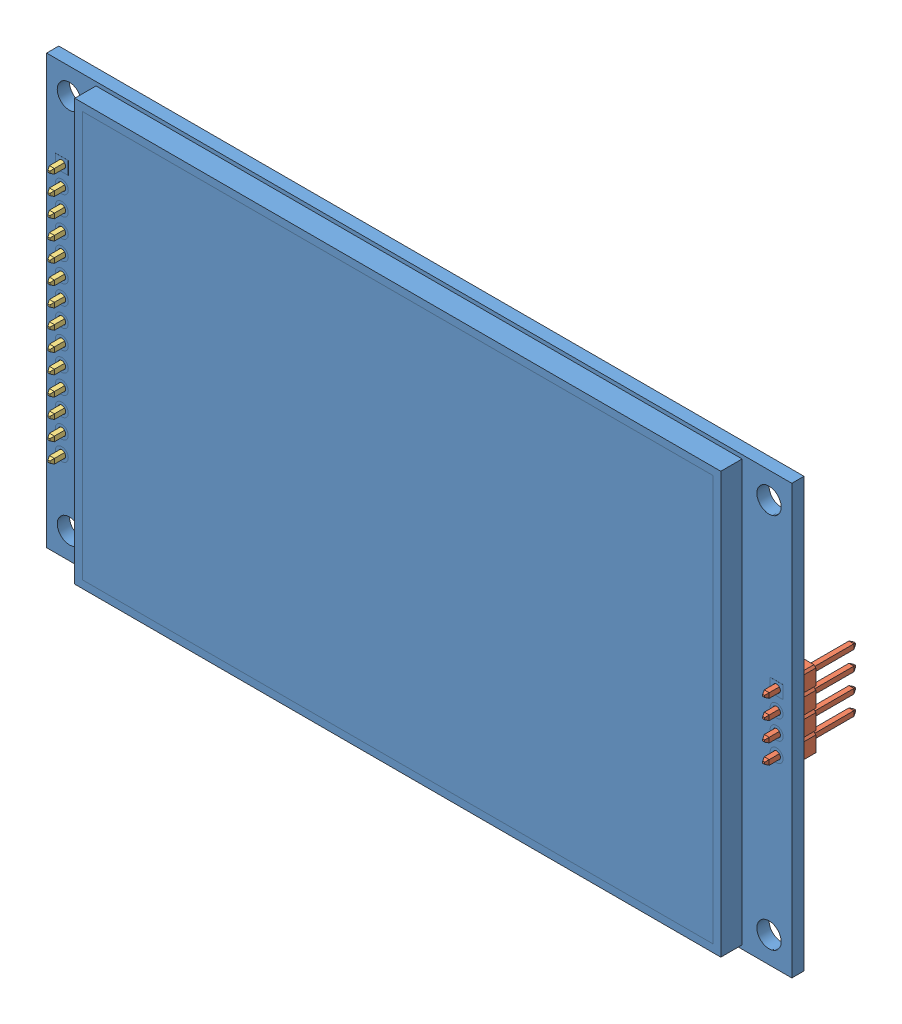
SolidWorks assembly LCD-3.5-ASSY, configuration Default. Lengths in mm.
Overall size (98 56.34 13.04).
3 component instances, 3 part files, 7 mates.
Components (placement in the parent):
- Circuit Board-1: Circuit Board [Default] at origin size (98 56.34 4.41)
- conn_01x04x2.54mm-1: conn_01x04x2.54mm [Default] at (47 3.81 -0.546) x (0 -1 0) z (1 0 0) size (10.16 11.94 2.54)
- conn_01x14x2.54mm-1: conn_01x14x2.54mm [Default] at (-47 16.51 -0.546) x (0 -1 0) z (1 0 0) size (35.55 11.94 2.54)
Mates (geometry in assembly coordinates):
- Concentric1: concentric aligned: circle of Circuit Board-1; line of ? through (-47 16.51 -10.0329) axis (0 0 1)
- Coincident6: coincident anti-aligned: plane of Circuit Board-1 through (0 0 -0.8) normal (0 0 -1); plane of conn_01x04x2.54mm-1 through (47 3.81 -0.8) normal (0 0 1)
- Concentric2: concentric anti-aligned: circle of Circuit Board-1; line of conn_01x04x2.54mm-1 through (47 3.81 3.0989) axis (0 0 -1)
- Coincident7: coincident anti-aligned: plane of Circuit Board-1 through (0 0 -0.8) normal (0 0 -1); plane of conn_01x14x2.54mm-1 through (-47 16.51 -0.8) normal (0 0 1)
- Concentric3: concentric aligned: circle of Circuit Board-1; line of conn_01x14x2.54mm-1 through (-47 16.51 -10.0329) axis (0 0 1)
- Parallel1: parallel aligned: plane of conn_01x14x2.54mm-1 through (-45.73 14.986 -0.546) normal (1 0 0); plane of assembly through (0 0 0) normal (1 0 0)
- Parallel2: parallel anti-aligned: plane of conn_01x04x2.54mm-1 through (45.73 2.794 -0.546) normal (-1 0 0); plane of assembly through (0 0 0) normal (1 0 0)
